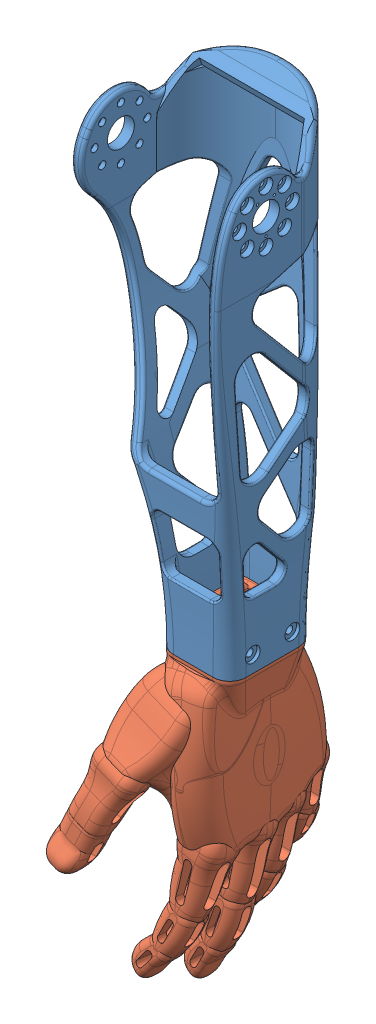
SolidWorks assembly arm_l3, configuration Default. Lengths in mm.
Overall size (55.2 228.71 65.03).
2 component instances, 2 part files, 3 mates.
Components (placement in the parent):
- arm_forearm_left-2: arm_forearm_left [MX-28-right] at (51.4657 156.3057 103.1131) size (55.2 137.66 53.14)
- arm_hand_left-1: arm_hand_left [left_fake_human_like_hand] at (40.8108 36.3057 99.1131) x (0 0 -1) z (0 -1 0) size (64.5 37.73 100.68)
Mates (geometry in assembly coordinates):
- Concentric1: concentric aligned: cylinder of arm_forearm_left-2 through (55.9608 41.3057 105.1131) axis (1 0 0) radius 1.1; cylinder of arm_hand_left-1 through (29.8108 41.3057 105.1131) axis (1 0 0) radius 1.1
- Concentric2: concentric aligned: cylinder of arm_forearm_left-2 through (55.9608 41.3057 93.1131) axis (1 0 0) radius 1.1; cylinder of arm_hand_left-1 through (29.8108 41.3057 93.1131) axis (1 0 0) radius 1.1
- Tangent3: tangent: face of arm_forearm_left-2; plane of arm_hand_left-1 through (32.9608 45.3057 107.1131) normal (-1 0 0)
